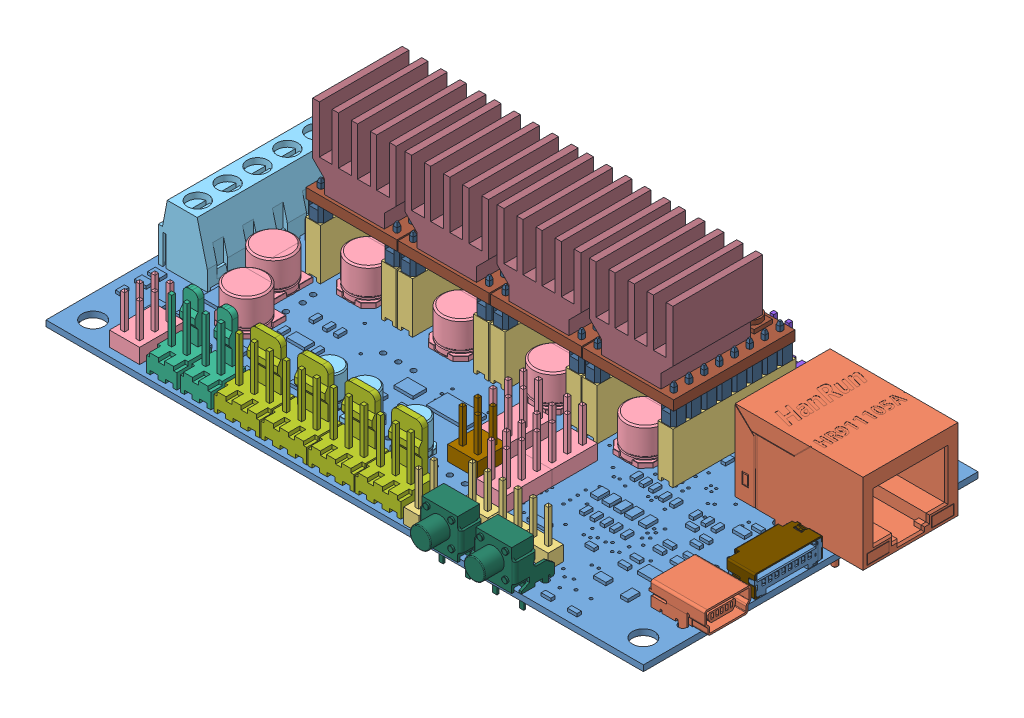
SolidWorks assembly X5miniV3, configuration Default. Lengths in mm.
Overall size (104.69 29.25 60.32).
81 component instances, 23 part files, 171 mates.
Components (placement in the parent):
- x5mv3 Board-1: x5mv3 Board [Default] at (-13.3104 0 19.6769) x (1 0 0) z (0 1 0) size (100 56 3.1)
- User Library-HR911105A-1: User Library-HR911105A [Default] at (54.6867 13.5 -4.0769) x (0 0 -1) z (1 0 0) size (15.88 16.5 21.4)
- female_header_a-bl254-eg-g08d-1: female_header_a-bl254-eg-g08d [Default] at (25.5608 0 -10.4185) x (0 0 -1) z (1 0 0) size (20.57 11.65 2.5)
- female_header_a-bl254-eg-g08d-2: female_header_a-bl254-eg-g08d [Default] at (12.8608 0 -10.4185) x (0 0 -1) z (1 0 0) size (20.57 11.65 2.5)
- female_header_a-bl254-eg-g08d-3: female_header_a-bl254-eg-g08d [Default] at (10.1067 0 -10.4585) x (0 0 -1) z (1 0 0) size (20.57 11.65 2.5)
- female_header_a-bl254-eg-g08d-4: female_header_a-bl254-eg-g08d [Default] at (-2.5933 0 -10.4585) x (0 0 -1) z (1 0 0) size (20.57 11.65 2.5)
- female_header_a-bl254-eg-g08d-5: female_header_a-bl254-eg-g08d [Default] at (-18.0466 0 -10.4485) x (0 0 -1) z (1 0 0) size (20.57 11.65 2.5)
- female_header_a-bl254-eg-g08d-6: female_header_a-bl254-eg-g08d [Default] at (-20.7999 0 -10.4585) x (0 0 1) z (-1 0 0) size (20.57 11.65 2.5)
- female_header_a-bl254-eg-g08d-7: female_header_a-bl254-eg-g08d [Default] at (-33.4999 0 -10.4585) x (0 0 -1) z (1 0 0) size (20.57 11.65 2.5)
- female_header_a-bl254-eg-g08d-8: female_header_a-bl254-eg-g08d [Default] at (-5.3466 0 -10.4485) x (0 0 -1) z (1 0 0) size (20.57 11.65 2.5)
- 2x3 Mhdr-1: 2x3 Mhdr [Default] at (18.6785 0 -15.1819) size (5.04 11.5 7.62)
- 2x3 Mhdr-2: 2x3 Mhdr [Default] at (3.3393 0 -15.141) size (5.04 11.5 7.62)
- 2x3 Mhdr-3: 2x3 Mhdr [Default] at (-11.9199 0 -15.2185) size (5.04 11.5 7.62)
- 2x3 Mhdr-4: 2x3 Mhdr [Default] at (-27.5066 0 -15.2352) size (5.04 11.5 7.62)
- tblock 6pin-1: tblock 6pin [Default] at (-48.7033 5 -4.5119) x (0 0 1) z (-1 0 0) size (30.6 13.5 8.2)
- Part6-1: Part6 [Default] at (-25.7172 1.5875 24.2537) x (0.999998 0 -0.001837) z (0.001837 0 0.999998) size (5.08 14.49 5.84)
- Part8-1: Part8 [Default] at (4.7613 1.5875 24.2217) x (0.999998 0 -0.001831) z (0.001831 0 0.999998) size (7.62 14.49 5.84)
- Part10-1: Part10 [Default] at (-11.4533 1.5875 -23.3498) x (-0.999999 0 0.00122) z (-0.00122 0 -0.999999) size (10.16 14.49 5.64)
- 2x3 Mhdr-5: 2x3 Mhdr [Default] at (-40.7388 0 19.013) size (5.04 11.5 7.62)
- Part6-2: Part6 [Default] at (-31.4251 1.5875 24.2537) x (0.999998 0 -0.001837) z (0.001837 0 0.999998) size (5.08 14.49 5.84)
- Part8-2: Part8 [Default] at (-18.8541 1.5875 24.2581) x (0.999998 0 -0.001831) z (0.001831 0 0.999998) size (7.62 14.49 5.84)
- Part8-3: Part8 [Default] at (-10.9823 1.5875 24.2217) x (0.999998 0 -0.001831) z (0.001831 0 0.999998) size (7.62 14.49 5.84)
- Part8-4: Part8 [Default] at (-3.0923 1.5875 24.2217) x (0.999998 0 -0.001831) z (0.001831 0 0.999998) size (7.62 14.49 5.84)
- Part10-2: Part10 [Default] at (-26.7899 1.5875 -23.3398) x (-0.999999 0 0.00122) z (-0.00122 0 -0.999999) size (10.16 14.49 5.64)
- Part10-3: Part10 [Default] at (3.8834 1.5875 -23.3398) x (-0.999999 0 0.00122) z (-0.00122 0 -0.999999) size (10.16 14.49 5.64)
- Part10-4: Part10 [Default] at (19.2134 1.5875 -23.3198) x (-0.999999 0 0.00122) z (-0.00122 0 -0.999999) size (10.16 14.49 5.64)
- 2x3 Mhdr-6: 2x3 Mhdr [Default] at (11.4847 0 2.2072) size (5.04 11.5 7.62)
- 2x3 Mhdr-7: 2x3 Mhdr [Default] at (11.4847 0 9.8271) size (5.04 11.5 7.62)
- 2x2 Mhdr-1: 2x2 Mhdr [Default] at (4.1345 0 7.289) size (5.04 11.5 5.08)
- 2x3 Mhdr-8: 2x3 Mhdr [Default] at (4.1345 0 2.209) size (5.04 11.5 7.62)
- Panucatt SD5984-1: Panucatt SD5984 [Default] at (19.1908 11.04 -10.4185) x (0 0 -1) z (1 0 0) size (20.32 22.85 15.24)
  - pin_header_aw140-eg-g08d-1: pin_header_aw140-eg-g08d [Default] at (0 0 6.37) size (20.22 11.2 2.5)
  - pin_header_aw140-eg-g08d-2: pin_header_aw140-eg-g08d [Default] at (0 0 -6.37) size (20.22 11.2 2.5)
  - SD5984_PCB-1: SD5984_PCB [Default] at origin size (20.32 3.05 15.24)
  - pin_header_aw140-eg-g02d-1: pin_header_aw140-eg-g02d [Default] at (8.89 0 -10.16) x (0 0 -1) z (1 0 0) size (5.08 11.2 2.5)
  - Panucatt Heatsink-1: Panucatt Heatsink [Default] at (-9.66 1.651 0) x (0 0 -1) z (1 0 0) size (14 13 15)
- Panucatt SD5984-2: Panucatt SD5984 [Default] at (3.7367 11.04 -10.4585) x (0 0 -1) z (1 0 0) size (20.32 22.85 15.24)
  - pin_header_aw140-eg-g08d-1: pin_header_aw140-eg-g08d [Default] at (0 0 6.37) size (20.22 11.2 2.5)
  - pin_header_aw140-eg-g08d-2: pin_header_aw140-eg-g08d [Default] at (0 0 -6.37) size (20.22 11.2 2.5)
  - SD5984_PCB-1: SD5984_PCB [Default] at origin size (20.32 3.05 15.24)
  - pin_header_aw140-eg-g02d-1: pin_header_aw140-eg-g02d [Default] at (8.89 0 -10.16) x (0 0 -1) z (1 0 0) size (5.08 11.2 2.5)
  - Panucatt Heatsink-1: Panucatt Heatsink [Default] at (-9.66 1.651 0) x (0 0 -1) z (1 0 0) size (14 13 15)
- Panucatt SD5984-3: Panucatt SD5984 [Default] at (-11.7166 11.04 -10.4485) x (0 0 -1) z (1 0 0) size (20.32 22.85 15.24)
  - pin_header_aw140-eg-g08d-1: pin_header_aw140-eg-g08d [Default] at (0 0 6.37) size (20.22 11.2 2.5)
  - pin_header_aw140-eg-g08d-2: pin_header_aw140-eg-g08d [Default] at (0 0 -6.37) size (20.22 11.2 2.5)
  - SD5984_PCB-1: SD5984_PCB [Default] at origin size (20.32 3.05 15.24)
  - pin_header_aw140-eg-g02d-1: pin_header_aw140-eg-g02d [Default] at (8.89 0 -10.16) x (0 0 -1) z (1 0 0) size (5.08 11.2 2.5)
  - Panucatt Heatsink-1: Panucatt Heatsink [Default] at (-9.66 1.651 0) x (0 0 -1) z (1 0 0) size (14 13 15)
- Panucatt SD5984-4: Panucatt SD5984 [Default] at (-27.1699 11.04 -10.4585) x (0 0 -1) z (1 0 0) size (20.32 22.85 15.24)
  - pin_header_aw140-eg-g08d-1: pin_header_aw140-eg-g08d [Default] at (0 0 6.37) size (20.22 11.2 2.5)
  - pin_header_aw140-eg-g08d-2: pin_header_aw140-eg-g08d [Default] at (0 0 -6.37) size (20.22 11.2 2.5)
  - SD5984_PCB-1: SD5984_PCB [Default] at origin size (20.32 3.05 15.24)
  - pin_header_aw140-eg-g02d-1: pin_header_aw140-eg-g02d [Default] at (8.89 0 -10.16) x (0 0 -1) z (1 0 0) size (5.08 11.2 2.5)
  - Panucatt Heatsink-1: Panucatt Heatsink [Default] at (-9.66 1.651 0) x (0 0 -1) z (1 0 0) size (14 13 15)
- female_header (3pin)_a-bl254-eg-g08d-2: female_header (3pin)_a-bl254-eg-g08d [Default] at (-34.7699 0 -19.3485) size (7.87 11.65 2.5)
- female_header (3pin)_a-bl254-eg-g08d-3: female_header (3pin)_a-bl254-eg-g08d [Default] at (-19.3166 0 -19.3385) size (7.87 11.65 2.5)
- female_header (3pin)_a-bl254-eg-g08d-4: female_header (3pin)_a-bl254-eg-g08d [Default] at (-3.8633 0 -19.3485) size (7.87 11.65 2.5)
- female_header (3pin)_a-bl254-eg-g08d-5: female_header (3pin)_a-bl254-eg-g08d [Default] at (11.5908 0 -19.3085) size (7.87 11.65 2.5)
- c-1825027-8-g1-3d-1: c-1825027-8-g1-3d [Default] at (16.9729 4.0132 29.0549) size (8.41 10.52 9.84)
- c-1825027-8-g1-3d-2: c-1825027-8-g1-3d [Default] at (25.9941 4.0132 29.0465) size (8.41 10.52 9.84)
- MINI Blade Fuse Type 2-1: MINI Blade Fuse Type 2 [Default] at (-37.6763 10.675 -12.4851) x (0 0 1) z (0 1 0) size (10.91 3.81 16.3)
- Fuse Holder-1: Fuse Holder [Default] at (-37.3642 1.5875 -12.5321) x (0.01278 0 -0.999918) z (0.999918 0 0.01278) size (14.68 11.18 4.75)
- 473093751 v1-2: 473093751 v1 [Default] at (47.6367 1.4 3.9232) x (0 0 1) z (-1 0 0) size (11.6 3.75 5.5)
  - 473093751_3-1: 473093751_3 [Default] at origin size (11.4 3.75 5.5)
  - 473093751_1_2-1: 473093751_1_2 [Default] at origin size (11.6 3.75 5.3)
- usb_a-usb_b-m5-c-1: usb_a-usb_b-m5-c [Default] at (51.2549 0 15.1151) x (0 0 -1) z (1 0 0) size (7.7 5.6 9.35)
- 2x1 Mhdr-1: 2x1 Mhdr [Default] at (9.5401 0 27.6608) x (0 0 -1) z (1 0 0) size (5.04 11.5 2.54)
- 2x1 Mhdr-2: 2x1 Mhdr [Default] at (13.1357 0 19.7332) size (5.04 11.5 2.54)
- 2x1 Mhdr-3: 2x1 Mhdr [Default] at (18.2157 0 19.7332) size (5.04 11.5 2.54)
- 2x1 Mhdr-4: 2x1 Mhdr [Default] at (23.2957 0 19.7332) size (5.04 11.5 2.54)
- Capacitor1-1: Capacitor1 [Default] at (37.0467 0.2085 -24.0618) x (0 0 1) z (-1 0 0) size (6.63 5.71 6.63)
- Capacitor1-2: Capacitor1 [Default] at (-27.3299 0.2085 -3.2918) x (-1 0 0) z (0 0 -1) size (6.63 5.71 6.63)
- Capacitor1-3: Capacitor1 [Default] at (-11.8766 0.2085 -3.2918) x (-1 0 0) z (0 0 -1) size (6.63 5.71 6.63)
- Capacitor1-4: Capacitor1 [Default] at (3.5767 0.2085 -3.2918) x (-1 0 0) z (0 0 -1) size (6.63 5.71 6.63)
- Capacitor1-5: Capacitor1 [Default] at (19.03 0.2085 -3.2918) x (-1 0 0) z (0 0 -1) size (6.63 5.71 6.63)
- Capacitor1-6: Capacitor1 [Default] at (-33.0633 0.2085 11.3781) x (-1 0 0) z (0 0 -1) size (6.63 5.71 6.63)
- Capacitor1-7: Capacitor1 [Default] at (-36.3733 0.2085 3.5781) x (0 0 -1) z (1 0 0) size (6.63 5.71 6.63)
- Capacitor1-8: Capacitor1 [Default] at (-37.3233 0.2085 -23.8118) x (0 0 1) z (-1 0 0) size (6.63 5.71 6.63)
- Capacitor2-1: Capacitor2 [Default] at (-0.0933 0.0406 16.0082) size (5.86 5.37 4.68)
- Capacitor2-2: Capacitor2 [Default] at (-8.5533 0.0406 16.0082) size (5.86 5.37 4.68)
- Capacitor2-3: Capacitor2 [Default] at (-14.4933 0.0406 16.0082) size (5.86 5.37 4.68)
Mates (geometry in assembly coordinates):
- Concentric1: concentric anti-aligned: cylinder of x5mv3 Board-1 through (48.6667 -0.991 -5.3918) axis (0 1 0) radius 0.4064; cylinder of User Library-HR911105A-1 through (48.6667 0 -5.3918) axis (0 -1 0) radius 0.5
- Parallel2: parallel aligned: plane of x5mv3 Board-1 through (49.9967 -0.991 27.9882) normal (1 0 0); plane of User Library-HR911105A-1 through (54.6867 0 -4.0769) normal (1 0 0)
- Coincident2: coincident anti-aligned: plane of x5mv3 Board-1 through (-13.3104 0 19.6769) normal (0 1 0); plane of User Library-HR911105A-1 through (54.6867 0 -4.0769) normal (0 -1 0)
- Coincident3: coincident: point of x5mv3 Board-1; point of assembly
- Coincident4: coincident anti-aligned: plane of x5mv3 Board-1 through (-13.3104 0 19.6769) normal (0 1 0); plane of female_header_a-bl254-eg-g08d-1 through (24.3108 0 -0.1335) normal (0 -1 0)
- Coincident5: coincident aligned: plane of x5mv3 Board-1 through (-13.3104 0 19.6769) normal (0 1 0); plane of assembly through (0 0 0) normal (0 1 0)
- Parallel3: parallel aligned: plane of x5mv3 Board-1 through (49.9967 -0.991 27.9882) normal (1 0 0); plane of assembly through (0 0 0) normal (1 0 0)
- Concentric5: concentric anti-aligned: cylinder of x5mv3 Board-1 through (25.5608 -0.991 -19.3085) axis (0 1 0) radius 0.45; circle of female_header_a-bl254-eg-g08d-1
- Concentric2: concentric anti-aligned: cylinder of x5mv3 Board-1 through (25.5608 -0.991 -1.5285) axis (0 1 0) radius 0.45; circle of female_header_a-bl254-eg-g08d-1
- Coincident9: coincident anti-aligned: plane of x5mv3 Board-1 through (-13.3104 0 19.6769) normal (0 1 0); plane of female_header_a-bl254-eg-g08d-2 through (13.6358 0 -0.1335) normal (0 -1 0)
- Concentric4: concentric anti-aligned: cylinder of x5mv3 Board-1 through (12.8608 -0.991 -1.5285) axis (0 1 0) radius 0.45; circle of female_header_a-bl254-eg-g08d-2
- Concentric3: concentric anti-aligned: cylinder of x5mv3 Board-1 through (12.8608 -0.991 -19.3085) axis (0 1 0) radius 0.45; circle of female_header_a-bl254-eg-g08d-2
- Coincident12: coincident anti-aligned: plane of x5mv3 Board-1 through (-13.3104 0 19.6769) normal (0 1 0); plane of female_header_a-bl254-eg-g08d-3 through (8.8567 0 -0.1735) normal (0 -1 0)
- Coincident13: coincident anti-aligned: plane of x5mv3 Board-1 through (-13.3104 0 19.6769) normal (0 1 0); plane of female_header_a-bl254-eg-g08d-4 through (-3.8433 0 -0.1735) normal (0 -1 0)
- Coincident14: coincident anti-aligned: plane of x5mv3 Board-1 through (-13.3104 0 19.6769) normal (0 1 0); plane of female_header_a-bl254-eg-g08d-6 through (-21.5749 0 -20.7435) normal (0 -1 0)
- Coincident15: coincident anti-aligned: plane of x5mv3 Board-1 through (-13.3104 0 19.6769) normal (0 1 0); plane of female_header_a-bl254-eg-g08d-5 through (-17.2716 0 -0.1635) normal (0 -1 0)
- Coincident16: coincident anti-aligned: plane of x5mv3 Board-1 through (-13.3104 0 19.6769) normal (0 1 0); plane of female_header_a-bl254-eg-g08d-7 through (-32.7249 0 -0.1735) normal (0 -1 0)
- Coincident17: coincident anti-aligned: plane of x5mv3 Board-1 through (-13.3104 0 19.6769) normal (0 1 0); plane of female_header_a-bl254-eg-g08d-8 through (-4.5716 0 -0.1635) normal (0 -1 0)
- Concentric6: concentric anti-aligned: cylinder of x5mv3 Board-1 through (10.1067 -0.991 -19.3485) axis (0 1 0) radius 0.45; circle of female_header_a-bl254-eg-g08d-3
- Concentric7: concentric anti-aligned: cylinder of x5mv3 Board-1 through (10.1067 -0.991 -1.5685) axis (0 1 0) radius 0.45; circle of female_header_a-bl254-eg-g08d-3
- Concentric8: concentric anti-aligned: cylinder of x5mv3 Board-1 through (-2.5933 -0.991 -19.3485) axis (0 1 0) radius 0.45; circle of female_header_a-bl254-eg-g08d-4
- Concentric9: concentric anti-aligned: cylinder of x5mv3 Board-1 through (-2.5933 -0.991 -1.5685) axis (0 1 0) radius 0.45; circle of female_header_a-bl254-eg-g08d-4
- Concentric10: concentric anti-aligned: cylinder of x5mv3 Board-1 through (-18.0466 -0.991 -19.3385) axis (0 1 0) radius 0.45; circle of female_header_a-bl254-eg-g08d-5
- Concentric11: concentric anti-aligned: cylinder of x5mv3 Board-1 through (-18.0466 -0.991 -1.5585) axis (0 1 0) radius 0.45; circle of female_header_a-bl254-eg-g08d-5
- Concentric12: concentric anti-aligned: cylinder of x5mv3 Board-1 through (-20.7999 -0.991 -19.3485) axis (0 1 0) radius 0.45; circle of female_header_a-bl254-eg-g08d-6
- Concentric13: concentric anti-aligned: cylinder of x5mv3 Board-1 through (-20.7999 -0.991 -1.5685) axis (0 1 0) radius 0.45; circle of female_header_a-bl254-eg-g08d-6
- Concentric16: concentric anti-aligned: cylinder of x5mv3 Board-1 through (-5.3466 -0.991 -19.3385) axis (0 1 0) radius 0.45; circle of female_header_a-bl254-eg-g08d-8
- Concentric14: concentric anti-aligned: cylinder of x5mv3 Board-1 through (-5.3466 -0.991 -1.5585) axis (0 1 0) radius 0.45; circle of female_header_a-bl254-eg-g08d-8
- Concentric15: concentric anti-aligned: cylinder of x5mv3 Board-1 through (-33.4999 -0.991 -19.3485) axis (0 1 0) radius 0.45; circle of female_header_a-bl254-eg-g08d-7
- Concentric17: concentric anti-aligned: cylinder of x5mv3 Board-1 through (-33.4999 -0.991 -1.5685) axis (0 1 0) radius 0.45; circle of female_header_a-bl254-eg-g08d-7
- Coincident27: coincident anti-aligned: plane of x5mv3 Board-1 through (-13.3104 0 19.6769) normal (0 1 0); plane of 2x3 Mhdr-1 through (18.6785 0 -7.5618) normal (0 -1 0)
- Coincident28: coincident anti-aligned: plane of x5mv3 Board-1 through (-13.3104 0 19.6769) normal (0 1 0); plane of 2x3 Mhdr-2 through (3.3393 0 -7.521) normal (0 -1 0)
- Coincident29: coincident anti-aligned: plane of x5mv3 Board-1 through (-13.3104 0 19.6769) normal (0 1 0); plane of 2x3 Mhdr-3 through (-11.9199 0 -7.5985) normal (0 -1 0)
- Coincident30: coincident anti-aligned: plane of x5mv3 Board-1 through (-13.3104 0 19.6769) normal (0 1 0); plane of 2x3 Mhdr-4 through (-27.5066 0 -7.6152) normal (0 -1 0)
- Concentric18: concentric anti-aligned: circle of 2x3 Mhdr-1; cylinder of x5mv3 Board-1 through (19.9285 -0.991 -13.9118) axis (0 1 0) radius 0.4445
- Concentric19: concentric anti-aligned: circle of 2x3 Mhdr-1; cylinder of x5mv3 Board-1 through (19.9285 -0.991 -8.8319) axis (0 1 0) radius 0.4445
- Concentric20: concentric anti-aligned: circle of 2x3 Mhdr-2; cylinder of x5mv3 Board-1 through (4.5893 -0.991 -13.871) axis (0 1 0) radius 0.4445
- Concentric21: concentric anti-aligned: circle of 2x3 Mhdr-2; cylinder of x5mv3 Board-1 through (4.5893 -0.991 -8.7911) axis (0 1 0) radius 0.4445
- Concentric22: concentric anti-aligned: circle of 2x3 Mhdr-3; cylinder of x5mv3 Board-1 through (-10.6699 -0.991 -13.9485) axis (0 1 0) radius 0.4445
- Concentric23: concentric anti-aligned: circle of 2x3 Mhdr-3; cylinder of x5mv3 Board-1 through (-10.6699 -0.991 -8.8685) axis (0 1 0) radius 0.4445
- Concentric24: concentric anti-aligned: circle of 2x3 Mhdr-4; cylinder of x5mv3 Board-1 through (-26.2566 -0.991 -13.9652) axis (0 1 0) radius 0.4445
- Concentric25: concentric anti-aligned: circle of 2x3 Mhdr-4; cylinder of x5mv3 Board-1 through (-26.2566 -0.991 -8.8852) axis (0 1 0) radius 0.4445
- Coincident31: coincident anti-aligned: plane of x5mv3 Board-1 through (-13.3104 0 19.6769) normal (0 1 0); plane of tblock 6pin-1 through (-48.7033 0 -19.5118) normal (0 -1 0)
- Concentric26: concentric anti-aligned: cylinder of x5mv3 Board-1 through (-44.6033 -0.991 -17.0118) axis (0 1 0) radius 0.65; circle of tblock 6pin-1
- Concentric27: concentric anti-aligned: cylinder of x5mv3 Board-1 through (-44.6033 -0.991 7.9881) axis (0 1 0) radius 0.65; circle of tblock 6pin-1
- Coincident34: coincident anti-aligned: plane of x5mv3 Board-1 through (-13.3104 0 19.6769) normal (0 1 0); plane of 2x3 Mhdr-5 through (-40.7388 0 26.633) normal (0 -1 0)
- Concentric28: concentric anti-aligned: cylinder of x5mv3 Board-1 through (-39.4888 -0.991 20.283) axis (0 1 0) radius 0.4445; circle of 2x3 Mhdr-5
- Concentric29: concentric anti-aligned: cylinder of x5mv3 Board-1 through (-39.4888 -0.991 25.363) axis (0 1 0) radius 0.4445; circle of 2x3 Mhdr-5
- Coincident35: coincident anti-aligned: plane of x5mv3 Board-1 through (-13.3104 0 19.6769) normal (0 1 0); plane of Part6-2 through (-34.061 0 27.3472) normal (0 -1 0)
- Coincident36: coincident anti-aligned: plane of x5mv3 Board-1 through (-13.3104 0 19.6769) normal (0 1 0); plane of Part8-2 through (-22.8108 0 27.354) normal (0 -1 0)
- Coincident37: coincident anti-aligned: plane of x5mv3 Board-1 through (-13.3104 0 19.6769) normal (0 1 0); plane of Part8-3 through (-14.939 0 27.3176) normal (0 -1 0)
- Coincident38: coincident anti-aligned: plane of x5mv3 Board-1 through (-13.3104 0 19.6769) normal (0 1 0); plane of Part6-1 through (-28.3531 0 27.3472) normal (0 -1 0)
- Coincident39: coincident anti-aligned: plane of x5mv3 Board-1 through (-13.3104 0 19.6769) normal (0 1 0); plane of Part8-4 through (-7.0491 0 27.3176) normal (0 -1 0)
- Coincident40: coincident anti-aligned: plane of x5mv3 Board-1 through (-13.3104 0 19.6769) normal (0 1 0); plane of Part8-1 through (0.8045 0 27.3176) normal (0 -1 0)
- Coincident41: coincident anti-aligned: plane of x5mv3 Board-1 through (-13.3104 0 19.6769) normal (0 1 0); plane of Part10-2 through (-21.5105 0 -26.4349) normal (0 -1 0)
- Coincident42: coincident anti-aligned: plane of x5mv3 Board-1 through (-13.3104 0 19.6769) normal (0 1 0); plane of Part10-3 through (9.1628 0 -26.4349) normal (0 -1 0)
- Coincident43: coincident anti-aligned: plane of x5mv3 Board-1 through (-13.3104 0 19.6769) normal (0 1 0); plane of Part10-4 through (24.4928 0 -26.4149) normal (0 -1 0)
- Coincident44: coincident anti-aligned: plane of x5mv3 Board-1 through (-13.3104 0 19.6769) normal (0 1 0); plane of Part10-1 through (-6.1738 0 -26.4449) normal (0 -1 0)
- Concentric30: concentric anti-aligned: cylinder of x5mv3 Board-1 through (-30.5999 -0.991 -23.3352) axis (0 1 0) radius 0.45; circle of Part10-2
- Concentric31: concentric anti-aligned: cylinder of x5mv3 Board-1 through (-22.9799 -0.991 -23.3445) axis (0 1 0) radius 0.45; circle of Part10-2
- Concentric32: concentric anti-aligned: cylinder of x5mv3 Board-1 through (-15.2633 -0.991 -23.3452) axis (0 1 0) radius 0.45; circle of Part10-1
- Concentric33: concentric anti-aligned: cylinder of x5mv3 Board-1 through (-7.6433 -0.991 -23.3545) axis (0 1 0) radius 0.45; circle of Part10-1
- Concentric34: concentric anti-aligned: cylinder of x5mv3 Board-1 through (0.0734 -0.991 -23.3352) axis (0 1 0) radius 0.45; circle of Part10-3
- Concentric35: concentric anti-aligned: cylinder of x5mv3 Board-1 through (7.6934 -0.991 -23.3445) axis (0 1 0) radius 0.45; circle of Part10-3
- Concentric36: concentric anti-aligned: cylinder of x5mv3 Board-1 through (15.4034 -0.991 -23.3152) axis (0 1 0) radius 0.45; circle of Part10-4
- Concentric37: concentric anti-aligned: cylinder of x5mv3 Board-1 through (23.0234 -0.991 -23.3245) axis (0 1 0) radius 0.45; circle of Part10-4
- Concentric38: concentric anti-aligned: cylinder of x5mv3 Board-1 through (-32.6951 -0.991 24.2561) axis (0 1 0) radius 0.5; circle of Part6-2
- Concentric39: concentric anti-aligned: cylinder of x5mv3 Board-1 through (-30.1551 -0.991 24.2514) axis (0 1 0) radius 0.5; circle of Part6-2
- Concentric40: concentric anti-aligned: cylinder of x5mv3 Board-1 through (-26.9872 -0.991 24.2561) axis (0 1 0) radius 0.5; circle of Part6-1
- Concentric41: concentric anti-aligned: cylinder of x5mv3 Board-1 through (-24.4472 -0.991 24.2514) axis (0 1 0) radius 0.5; circle of Part6-1
- Concentric42: concentric anti-aligned: cylinder of x5mv3 Board-1 through (-21.3941 -0.991 24.2627) axis (0 1 0) radius 0.5; circle of Part8-2
- Concentric43: concentric anti-aligned: cylinder of x5mv3 Board-1 through (-16.3141 -0.991 24.2534) axis (0 1 0) radius 0.5; circle of Part8-2
- Concentric44: concentric anti-aligned: cylinder of x5mv3 Board-1 through (-13.5223 -0.991 24.2263) axis (0 1 0) radius 0.5; circle of Part8-3
- Concentric45: concentric anti-aligned: cylinder of x5mv3 Board-1 through (-8.4423 -0.991 24.217) axis (0 1 0) radius 0.5; circle of Part8-3
- Concentric46: concentric anti-aligned: cylinder of x5mv3 Board-1 through (-5.6323 -0.991 24.2263) axis (0 1 0) radius 0.5; circle of Part8-4
- Concentric47: concentric anti-aligned: cylinder of x5mv3 Board-1 through (-0.5523 -0.991 24.217) axis (0 1 0) radius 0.5; circle of Part8-4
- Concentric48: concentric anti-aligned: cylinder of x5mv3 Board-1 through (2.2213 -0.991 24.2263) axis (0 1 0) radius 0.5; circle of Part8-1
- Concentric49: concentric anti-aligned: cylinder of x5mv3 Board-1 through (7.3013 -0.991 24.217) axis (0 1 0) radius 0.5; circle of Part8-1
- Coincident53: coincident anti-aligned: plane of x5mv3 Board-1 through (-13.3104 0 19.6769) normal (0 1 0); plane of 2x3 Mhdr-6 through (11.4847 0 9.8271) normal (0 -1 0)
- Coincident54: coincident anti-aligned: plane of x5mv3 Board-1 through (-13.3104 0 19.6769) normal (0 1 0); plane of 2x3 Mhdr-7 through (11.4847 0 17.4472) normal (0 -1 0)
- Concentric50: concentric anti-aligned: cylinder of x5mv3 Board-1 through (12.7347 -0.991 3.4771) axis (0 1 0) radius 0.4445; circle of 2x3 Mhdr-6
- Concentric51: concentric anti-aligned: cylinder of x5mv3 Board-1 through (12.7347 -0.991 8.5572) axis (0 1 0) radius 0.4445; circle of 2x3 Mhdr-6
- Concentric52: concentric anti-aligned: cylinder of x5mv3 Board-1 through (12.7347 -0.991 11.0971) axis (0 1 0) radius 0.4445; circle of 2x3 Mhdr-7
- Concentric53: concentric anti-aligned: cylinder of x5mv3 Board-1 through (12.7347 -0.991 16.1772) axis (0 1 0) radius 0.4445; circle of 2x3 Mhdr-7
- Coincident63: coincident anti-aligned: plane of x5mv3 Board-1 through (-13.3104 0 19.6769) normal (0 1 0); plane of 2x2 Mhdr-1 through (4.1345 0 14.909) normal (0 -1 0)
- Coincident64: coincident anti-aligned: plane of x5mv3 Board-1 through (-13.3104 0 19.6769) normal (0 1 0); plane of 2x3 Mhdr-8 through (4.1345 0 9.829) normal (0 -1 0)
- Concentric67: concentric anti-aligned: cylinder of x5mv3 Board-1 through (5.3845 -0.991 3.479) axis (0 1 0) radius 0.4445; circle of 2x3 Mhdr-8
- Concentric68: concentric anti-aligned: cylinder of x5mv3 Board-1 through (5.3845 -0.991 8.559) axis (0 1 0) radius 0.4445; circle of 2x3 Mhdr-8
- Concentric69: concentric anti-aligned: cylinder of x5mv3 Board-1 through (5.3845 -0.991 11.099) axis (0 1 0) radius 0.4445; circle of 2x2 Mhdr-1
- Coincident65: coincident aligned: plane of 2x2 Mhdr-1 through (9.1745 0 14.909) normal (1 0 0); plane of 2x3 Mhdr-8 through (9.1745 0 9.829) normal (1 0 0)
- Coincident66: coincident anti-aligned: plane of female_header_a-bl254-eg-g08d-1 through (26.8108 8.5 -0.1335) normal (0 1 0); plane of Panucatt SD5984-1/pin_header_aw140-eg-g08d-1 through (26.8108 8.5 -2.6985) normal (0 -1 0)
- Coincident67: coincident anti-aligned: plane of female_header_a-bl254-eg-g08d-1 through (26.8108 8.5 -0.1335) normal (0 1 0); plane of Panucatt SD5984-2/pin_header_aw140-eg-g08d-1 through (11.3567 8.5 -2.7385) normal (0 -1 0)
- Coincident68: coincident anti-aligned: plane of female_header_a-bl254-eg-g08d-1 through (26.8108 8.5 -0.1335) normal (0 1 0); plane of Panucatt SD5984-3/pin_header_aw140-eg-g08d-1 through (-4.0966 8.5 -2.7285) normal (0 -1 0)
- Coincident69: coincident anti-aligned: plane of female_header_a-bl254-eg-g08d-1 through (26.8108 8.5 -0.1335) normal (0 1 0); plane of Panucatt SD5984-4/pin_header_aw140-eg-g08d-1 through (-19.5499 8.5 -2.7385) normal (0 -1 0)
- Concentric72: concentric anti-aligned: circle of female_header_a-bl254-eg-g08d-1; circle of Panucatt SD5984-1/pin_header_aw140-eg-g08d-1
- Parallel4: parallel aligned: plane of female_header_a-bl254-eg-g08d-1 through (26.8108 0 -0.1335) normal (1 0 0); plane of Panucatt SD5984-1/SD5984_PCB-1 through (26.8108 12.691 -0.2585) normal (1 0 0)
- Concentric74: concentric anti-aligned: circle of female_header_a-bl254-eg-g08d-3; circle of Panucatt SD5984-2/pin_header_aw140-eg-g08d-1
- Parallel5: parallel aligned: plane of female_header_a-bl254-eg-g08d-3 through (11.3567 0 -0.1735) normal (1 0 0); plane of Panucatt SD5984-2/SD5984_PCB-1 through (11.3567 12.691 -0.2985) normal (1 0 0)
- Concentric75: concentric anti-aligned: circle of female_header_a-bl254-eg-g08d-8; circle of Panucatt SD5984-3/pin_header_aw140-eg-g08d-1
- Parallel6: parallel aligned: plane of female_header_a-bl254-eg-g08d-8 through (-4.0966 0 -0.1635) normal (1 0 0); plane of Panucatt SD5984-3/SD5984_PCB-1 through (-4.0966 12.691 -0.2885) normal (1 0 0)
- Concentric76: concentric anti-aligned: circle of female_header_a-bl254-eg-g08d-6; circle of Panucatt SD5984-4/pin_header_aw140-eg-g08d-1
- Parallel7: parallel aligned: plane of female_header_a-bl254-eg-g08d-6 through (-19.5499 8.5 -20.7435) normal (1 0 0); plane of Panucatt SD5984-4/SD5984_PCB-1 through (-19.5499 12.691 -0.2985) normal (1 0 0)
- Coincident79: coincident anti-aligned: plane of x5mv3 Board-1 through (-13.3104 0 19.6769) normal (0 1 0); plane of female_header (3pin)_a-bl254-eg-g08d-2 through (-45.0549 0 -20.5985) normal (0 -1 0)
- Coincident80: coincident anti-aligned: plane of x5mv3 Board-1 through (-13.3104 0 19.6769) normal (0 1 0); plane of female_header (3pin)_a-bl254-eg-g08d-3 through (-29.6016 0 -20.5885) normal (0 -1 0)
- Coincident81: coincident anti-aligned: plane of x5mv3 Board-1 through (-13.3104 0 19.6769) normal (0 1 0); plane of female_header (3pin)_a-bl254-eg-g08d-4 through (-14.1483 0 -20.5985) normal (0 -1 0)
- Coincident82: coincident anti-aligned: plane of x5mv3 Board-1 through (-13.3104 0 19.6769) normal (0 1 0); plane of female_header (3pin)_a-bl254-eg-g08d-5 through (1.3058 0 -20.5585) normal (0 -1 0)
- Concentric77: concentric anti-aligned: cylinder of x5mv3 Board-1 through (-30.9599 -0.991 -19.3485) axis (0 1 0) radius 0.4445; circle of female_header (3pin)_a-bl254-eg-g08d-2
- Concentric78: concentric anti-aligned: cylinder of x5mv3 Board-1 through (-25.8799 -0.991 -19.3485) axis (0 1 0) radius 0.4445; circle of female_header (3pin)_a-bl254-eg-g08d-2
- Concentric79: concentric anti-aligned: cylinder of x5mv3 Board-1 through (-15.5066 -0.991 -19.3385) axis (0 1 0) radius 0.4445; circle of female_header (3pin)_a-bl254-eg-g08d-3
- Concentric80: concentric anti-aligned: cylinder of x5mv3 Board-1 through (-10.4266 -0.991 -19.3385) axis (0 1 0) radius 0.4445; circle of female_header (3pin)_a-bl254-eg-g08d-3
- Concentric81: concentric anti-aligned: cylinder of x5mv3 Board-1 through (-0.0533 -0.991 -19.3485) axis (0 1 0) radius 0.4445; circle of female_header (3pin)_a-bl254-eg-g08d-4
- Concentric82: concentric anti-aligned: cylinder of x5mv3 Board-1 through (5.0267 -0.991 -19.3485) axis (0 1 0) radius 0.4445; circle of female_header (3pin)_a-bl254-eg-g08d-4
- Concentric83: concentric anti-aligned: cylinder of x5mv3 Board-1 through (15.4008 -0.991 -19.3085) axis (0 1 0) radius 0.4445; circle of female_header (3pin)_a-bl254-eg-g08d-5
- Concentric84: concentric anti-aligned: cylinder of x5mv3 Board-1 through (20.4808 -0.991 -19.3085) axis (0 1 0) radius 0.4445; circle of female_header (3pin)_a-bl254-eg-g08d-5
- Coincident83: coincident anti-aligned: plane of x5mv3 Board-1 through (-13.3104 0 19.6769) normal (0 1 0); plane of c-1825027-8-g1-3d-1 through (20.5289 0 27.9373) normal (0 -1 0)
- Concentric86: concentric anti-aligned: cylinder of x5mv3 Board-1 through (19.2208 -0.991 26.4642) axis (0 1 0) radius 0.4; circle of c-1825027-8-g1-3d-1
- Parallel8: parallel aligned: plane of x5mv3 Board-1 through (-50.0033 -0.991 27.9882) normal (0 0 1); plane of c-1825027-8-g1-3d-1 through (16.9729 4.0132 29.0549) normal (0 0 1)
- Concentric88: concentric anti-aligned: cylinder of x5mv3 Board-1 through (28.242 -0.991 26.4557) axis (0 1 0) radius 0.4; circle of c-1825027-8-g1-3d-2
- Coincident85: coincident anti-aligned: plane of x5mv3 Board-1 through (-13.3104 0 19.6769) normal (0 1 0); plane of c-1825027-8-g1-3d-2 through (29.5501 0 27.9289) normal (0 -1 0)
- Parallel9: parallel aligned: plane of x5mv3 Board-1 through (-50.0033 -0.991 27.9882) normal (0 0 1); plane of c-1825027-8-g1-3d-2 through (25.9941 4.0132 29.0465) normal (0 0 1)
- Coincident89: coincident anti-aligned: plane of x5mv3 Board-1 through (-13.3104 0 19.6769) normal (0 1 0); plane of Fuse Holder-1 through (-35.0833 0 -5.1618) normal (0 -1 0)
- Coincident98: coincident: line of x5mv3 Board-1 through (-37.3413 0 -14.3264) axis (0.01278 0 -0.999918); plane of Fuse Holder-1 through (-37.3642 1.5875 -12.5321) normal (0.999918 0 0.01278)
- Concentric89: concentric anti-aligned: circle of MINI Blade Fuse Type 2-1; circle of Fuse Holder-1
- Coincident99: coincident anti-aligned: plane of MINI Blade Fuse Type 2-1 through (-37.6763 3.175 -16.4351) normal (0 -1 0); plane of Fuse Holder-1 through (-35.0833 3.175 -5.1618) normal (0 1 0)
- Coincident100: coincident anti-aligned: plane of x5mv3 Board-1 through (-13.3104 0 19.6769) normal (0 1 0); plane of 473093751 v1-2/473093751_3-1 through (46.5467 0 9.3232) normal (0 -1 0)
- Distance3: distance = 0.06 mm aligned: plane of 473093751 v1-2/473093751_1_2-1 through (49.9367 1.4 3.9232) normal (1 0 0); plane of x5mv3 Board-1 through (49.9967 -0.991 27.9882) normal (1 0 0)
- Distance4: distance = 2 mm anti-aligned: plane of 473093751 v1-2/473093751_3-1 through (49.9367 2.8015 -2.0768) normal (0 0 -1); plane of User Library-HR911105A-1 through (33.2867 0 -4.0769) normal (0 0 1)
- Coincident103: coincident anti-aligned: plane of x5mv3 Board-1 through (-13.3104 0 19.6769) normal (0 1 0); plane of usb_a-usb_b-m5-c-1 through (52.2549 0 15.1151) normal (0 -1 0)
- Concentric90: concentric anti-aligned: cylinder of x5mv3 Board-1 through (47.5049 -0.991 11.4158) axis (0 1 0) radius 0.7; circle of usb_a-usb_b-m5-c-1
- Parallel11: parallel aligned: plane of x5mv3 Board-1 through (49.9967 -0.991 27.9882) normal (1 0 0); plane of usb_a-usb_b-m5-c-1 through (51.2549 1.95 19.1151) normal (1 0 0)
- Concentric92: concentric anti-aligned: cylinder of x5mv3 Board-1 through (10.8101 -0.991 26.4108) axis (0 1 0) radius 0.4445; circle of 2x1 Mhdr-1
- Coincident106: coincident anti-aligned: plane of x5mv3 Board-1 through (-13.3104 0 19.6769) normal (0 1 0); plane of 2x1 Mhdr-1 through (17.1601 0 27.6608) normal (0 -1 0)
- Parallel12: parallel aligned: plane of x5mv3 Board-1 through (-50.0033 -0.991 27.9882) normal (0 0 1); plane of 2x1 Mhdr-1 through (17.1601 0 27.6608) normal (0 0 1)
- Concentric93: concentric anti-aligned: cylinder of x5mv3 Board-1 through (14.3857 -0.991 21.0032) axis (0 1 0) radius 0.4445; circle of 2x1 Mhdr-2
- Concentric94: concentric anti-aligned: cylinder of x5mv3 Board-1 through (19.4657 -0.991 21.0032) axis (0 1 0) radius 0.4445; circle of 2x1 Mhdr-3
- Concentric95: concentric anti-aligned: cylinder of x5mv3 Board-1 through (24.5457 -0.991 21.0032) axis (0 1 0) radius 0.4445; circle of 2x1 Mhdr-4
- Coincident108: coincident aligned: plane of 2x1 Mhdr-2 through (13.1357 -3 22.2731) normal (0 0 1); plane of 2x1 Mhdr-3 through (18.2157 -3 22.2731) normal (0 0 1)
- Coincident109: coincident anti-aligned: plane of x5mv3 Board-1 through (-13.3104 0 19.6769) normal (0 1 0); plane of 2x1 Mhdr-2 through (13.1357 0 27.3531) normal (0 -1 0)
- Coincident110: coincident anti-aligned: plane of x5mv3 Board-1 through (-13.3104 0 19.6769) normal (0 1 0); plane of 2x1 Mhdr-3 through (18.2157 0 27.3531) normal (0 -1 0)
- Coincident111: coincident anti-aligned: plane of x5mv3 Board-1 through (-13.3104 0 19.6769) normal (0 1 0); plane of 2x1 Mhdr-4 through (23.2957 0 27.3531) normal (0 -1 0)
- Parallel13: parallel aligned: plane of x5mv3 Board-1 through (-50.0033 -0.991 27.9882) normal (0 0 1); plane of 2x1 Mhdr-4 through (23.2957 -3 22.2731) normal (0 0 1)
- Coincident113: coincident anti-aligned: plane of x5mv3 Board-1 through (-13.3104 0 19.6769) normal (0 1 0); plane of Capacitor1-1 through (37.0467 0 -24.0618) normal (0 -1 0)
- Distance5: distance = 12.95 mm: point of Capacitor1-1; plane of x5mv3 Board-1 through (49.9967 -0.991 27.9882) normal (1 0 0)
- Distance6: distance = 3.95 mm: point of Capacitor1-1; plane of x5mv3 Board-1 through (49.9967 -0.991 -28.0119) normal (0 0 -1)
- Parallel14: parallel aligned: plane of x5mv3 Board-1 through (49.9967 -0.991 27.9882) normal (1 0 0); plane of Capacitor1-1 through (40.3617 0.0514 -24.0618) normal (1 0 0)
- Coincident117: coincident anti-aligned: plane of x5mv3 Board-1 through (-13.3104 0 19.6769) normal (0 1 0); plane of Capacitor1-2 through (-27.3299 0 -3.2918) normal (0 -1 0)
- Distance7: distance = 24.72 mm: point of Capacitor1-2; plane of x5mv3 Board-1 through (49.9967 -0.991 -28.0119) normal (0 0 -1)
- Distance8: distance = 4.92 mm: point of Capacitor1-2; plane of female_header_a-bl254-eg-g08d-7 through (-32.2499 0 -0.1735) normal (1 0 0)
- Parallel15: parallel aligned: plane of female_header_a-bl254-eg-g08d-7 through (-33.4999 4.101 -0.1735) normal (0 0 1); plane of Capacitor1-2 through (-27.3299 0.0514 0.0231) normal (0 0 1)
- Coincident121: coincident anti-aligned: plane of x5mv3 Board-1 through (-13.3104 0 19.6769) normal (0 1 0); plane of Capacitor1-8 through (-37.3233 0 -23.8118) normal (0 -1 0)
- Coincident122: coincident anti-aligned: plane of x5mv3 Board-1 through (-13.3104 0 19.6769) normal (0 1 0); plane of Capacitor1-7 through (-36.3733 0 3.5781) normal (0 -1 0)
- Coincident123: coincident anti-aligned: plane of x5mv3 Board-1 through (-13.3104 0 19.6769) normal (0 1 0); plane of Capacitor1-6 through (-33.0633 0 11.3781) normal (0 -1 0)
- Distance9: distance = 4.2 mm: point of Capacitor1-8; plane of x5mv3 Board-1 through (49.9967 -0.991 -28.0119) normal (0 0 -1)
- Distance10: distance = 12.68 mm: point of Capacitor1-8; plane of x5mv3 Board-1 through (-50.0033 -0.991 -28.0119) normal (-1 0 0)
- Parallel16: parallel aligned: plane of x5mv3 Board-1 through (49.9967 -0.991 -28.0119) normal (0 0 -1); plane of Capacitor1-8 through (-37.3233 0.0514 -27.1268) normal (0 0 -1)
- Distance11: distance = 31.59 mm: point of Capacitor1-7; plane of x5mv3 Board-1 through (49.9967 -0.991 -28.0119) normal (0 0 -1)
- Distance12: distance = 13.63 mm: point of Capacitor1-7; plane of x5mv3 Board-1 through (-50.0033 -0.991 -28.0119) normal (-1 0 0)
- Parallel17: parallel aligned: plane of x5mv3 Board-1 through (-50.0033 -0.991 -28.0119) normal (-1 0 0); plane of Capacitor1-7 through (-39.6883 0.0514 3.5781) normal (-1 0 0)
- Distance13: distance = 16.94 mm: point of Capacitor1-6; plane of x5mv3 Board-1 through (-50.0033 -0.991 -28.0119) normal (-1 0 0)
- Distance14: distance = 39.39 mm: point of Capacitor1-6; plane of x5mv3 Board-1 through (49.9967 -0.991 -28.0119) normal (0 0 -1)
- Parallel18: parallel aligned: plane of x5mv3 Board-1 through (49.9967 -0.991 -28.0119) normal (0 0 -1); plane of Capacitor1-6 through (-33.0633 0.0514 8.0632) normal (0 0 -1)
- Coincident133: coincident anti-aligned: plane of x5mv3 Board-1 through (-13.3104 0 19.6769) normal (0 1 0); plane of Capacitor2-1 through (-0.0933 0 16.015) normal (0 -1 0)
- Coincident134: coincident anti-aligned: plane of x5mv3 Board-1 through (-13.3104 0 19.6769) normal (0 1 0); plane of Capacitor2-2 through (-8.5533 0 16.015) normal (0 -1 0)
- Coincident135: coincident anti-aligned: plane of x5mv3 Board-1 through (-13.3104 0 19.6769) normal (0 1 0); plane of Capacitor2-3 through (-14.4933 0 16.015) normal (0 -1 0)
- Distance15: distance = 49.91 mm: point of Capacitor2-1; plane of x5mv3 Board-1 through (-50.0033 -0.991 -28.0119) normal (-1 0 0)
- Distance16: distance = 8.46 mm: point of Capacitor2-1; point of Capacitor2-2
- Distance17: distance = 14.4 mm: point of Capacitor2-1; point of Capacitor2-3
- Distance18: distance = 11.98 mm: point of Capacitor2-1; plane of x5mv3 Board-1 through (-50.0033 -0.991 27.9882) normal (0 0 1)
- Coincident140: coincident aligned: plane of Capacitor2-1 through (-0.0933 0.0483 18.1743) normal (0 0 1); plane of Capacitor2-2 through (-8.5533 0.0483 18.1743) normal (0 0 1)
- Coincident141: coincident aligned: plane of Capacitor2-1 through (-0.0933 0.0483 18.1743) normal (0 0 1); plane of Capacitor2-3 through (-14.4933 0.0483 18.1743) normal (0 0 1)
- Parallel19: parallel aligned: plane of Capacitor2-1 through (-0.0933 0.0483 18.1743) normal (0 0 1); plane of x5mv3 Board-1 through (-50.0033 -0.991 27.9882) normal (0 0 1)
